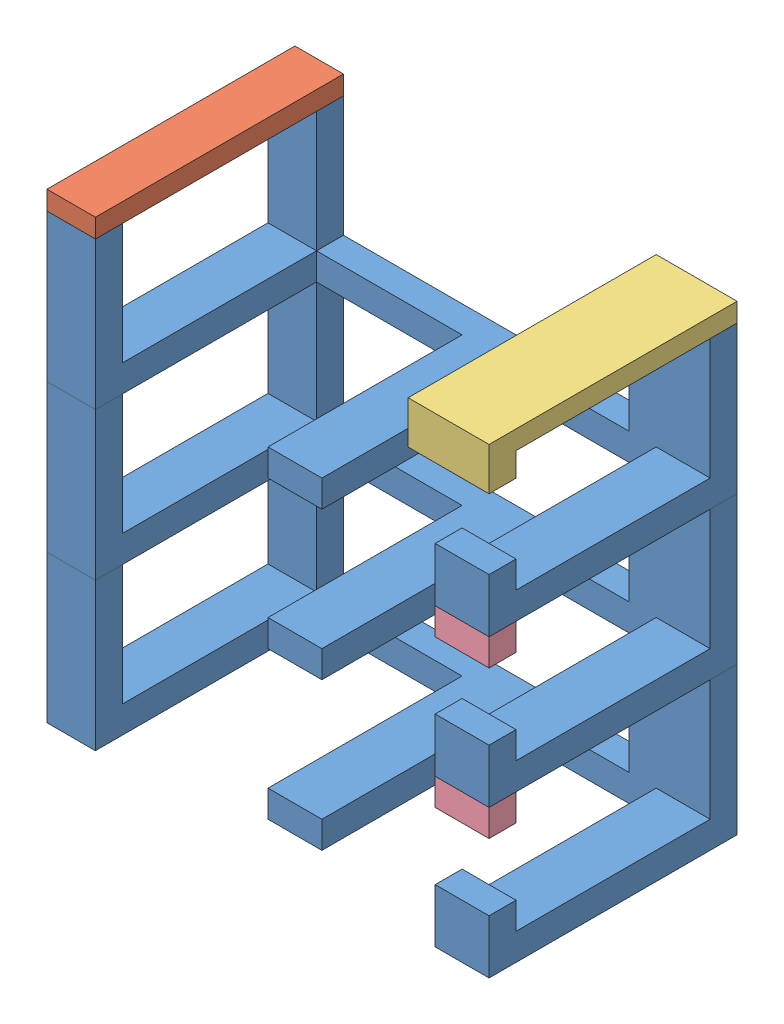
SolidWorks assembly Base final, configuration Predeterminado. Lengths in mm.
Overall size (82 85.7 46).
7 component instances, 4 part files, 18 mates.
Components (placement in the parent):
- Base electrovalvulas-1: Base electrovalvulas [Predeterminado] at (-5.4506 33.8045 -23) size (82 27.4 46)
- Base electrovalvulas-2: Base electrovalvulas [Predeterminado] at (-5.4506 88.6045 -23) size (82 27.4 46)
- Base electrovalvulas-3: Base electrovalvulas [Predeterminado] at (-5.4506 61.2045 -23) size (82 27.4 46)
- tope izquierdo base electro-1: tope izquierdo base electro [Predeterminado] at (7.3318 82.0348 -23) size (9 3.5 46)
- Tope derecho base electro-1: Tope derecho base electro [Predeterminado] at (33.8664 65.9993 -23) size (15.01 7.92 46)
- tope superior base-2: tope superior base [Predeterminado] at (59.3155 2.1974 18) size (10 5 5)
- tope superior base-3: tope superior base [Predeterminado] at (59.3155 29.5974 18) size (10 5 5)
Mates (geometry in assembly coordinates):
- Coincidente1: coincident anti-aligned: plane of Base electrovalvulas-1 through (-5.4506 32.7525 -23) normal (0 1 0); plane of Base electrovalvulas-3 through (-64.2232 32.7525 -18) normal (0 -1 0)
- Coincidente2: coincident aligned: plane of Base electrovalvulas-1 through (17.7768 5.3525 -18) normal (1 0 0); plane of Base electrovalvulas-3 through (17.7768 32.7525 -18) normal (1 0 0)
- Coincidente3: coincident aligned: plane of Base electrovalvulas-1 through (-5.4506 33.8045 23) normal (0 0 1); plane of Base electrovalvulas-3 through (-5.4506 61.2045 23) normal (0 0 1)
- Coincidente4: coincident anti-aligned: plane of Base electrovalvulas-2 through (-64.2232 60.1525 -18) normal (0 -1 0); plane of Base electrovalvulas-3 through (-5.4506 60.1525 -23) normal (0 1 0)
- Coincidente5: coincident aligned: plane of Base electrovalvulas-2 through (17.7768 60.1525 -18) normal (1 0 0); plane of Base electrovalvulas-3 through (17.7768 32.7525 -18) normal (1 0 0)
- Coincidente6: coincident aligned: plane of Base electrovalvulas-2 through (-5.4506 88.6045 23) normal (0 0 1); plane of Base electrovalvulas-3 through (-5.4506 61.2045 23) normal (0 0 1)
- Coincidente8: coincident aligned: plane of Base electrovalvulas-2 through (-5.4506 88.6045 23) normal (0 0 1); plane of tope izquierdo base electro-1 through (7.3318 82.0348 23) normal (0 0 1)
- Coincidente10: coincident anti-aligned: plane of Base electrovalvulas-2 through (-5.4506 87.5525 -23) normal (0 1 0); plane of Tope derecho base electro-1 through (17.7768 87.5525 18) normal (0 -1 0)
- Coincidente11: coincident aligned: plane of Base electrovalvulas-2 through (-5.4506 88.6045 -23) normal (0 0 -1); plane of Tope derecho base electro-1 through (33.8664 65.9993 -23) normal (0 0 -1)
- Coincidente12: coincident aligned: plane of Base electrovalvulas-2 through (17.7768 60.1525 -18) normal (1 0 0); plane of Tope derecho base electro-1 through (17.7768 91.0525 18) normal (1 0 0)
- Coincidente13: coincident anti-aligned: plane of Base electrovalvulas-2 through (-64.2232 60.1525 -18) normal (0 -1 0); plane of tope superior base-3 through (7.7768 60.1525 23) normal (0 1 0)
- Coincidente14: coincident aligned: plane of Base electrovalvulas-2 through (-5.4506 88.6045 23) normal (0 0 1); plane of tope superior base-3 through (59.3155 29.5974 23) normal (0 0 1)
- Coincidente15: coincident aligned: plane of Base electrovalvulas-2 through (17.7768 60.1525 -18) normal (1 0 0); plane of tope superior base-3 through (17.7768 60.1525 23) normal (1 0 0)
- Coincidente16: coincident anti-aligned: plane of Base electrovalvulas-3 through (-64.2232 32.7525 -18) normal (0 -1 0); plane of tope superior base-2 through (7.7768 32.7525 23) normal (0 1 0)
- Coincidente17: coincident aligned: plane of Base electrovalvulas-3 through (17.7768 32.7525 -18) normal (1 0 0); plane of tope superior base-2 through (17.7768 32.7525 23) normal (1 0 0)
- Coincidente18: coincident aligned: plane of Base electrovalvulas-3 through (-5.4506 61.2045 23) normal (0 0 1); plane of tope superior base-2 through (59.3155 2.1974 23) normal (0 0 1)
- Coincidente25: coincident aligned: plane of Base electrovalvulas-2 through (-64.2232 65.1525 -18) normal (-1 0 0); plane of tope izquierdo base electro-1 through (-64.2232 87.5525 23) normal (-1 0 0)
- Coincidente26: coincident aligned: plane of Base electrovalvulas-2 through (-5.4506 88.6045 -23) normal (0 0 -1); plane of tope izquierdo base electro-1 through (7.3318 82.0348 -23) normal (0 0 -1)
